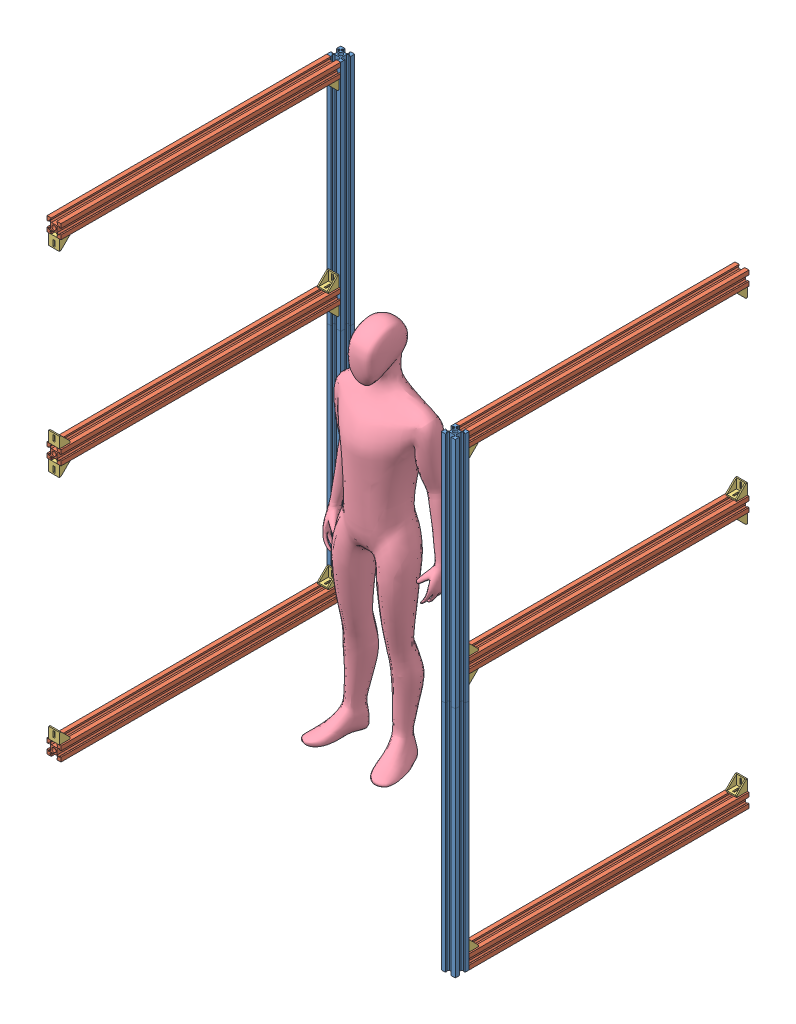
SolidWorks assembly FullFrameAssem, configuration Default. Lengths in mm.
Overall size (1732.26 2024.74 1278.93).
31 component instances, 4 part files, 10 mates.
Components (placement in the parent):
- RearSide-1: RearSide [Default] at (-737.6426 130.0792 3578.5624) x (0 0 -1) z (1 0 0) size (1260 2000 60)
  - AluminiumBar2M-1: AluminiumBar2M [Default] at (445.2282 96.0912 679.1807) size (60 2000 60)
    - AluminiumBar1M-1: AluminiumBar1M [Default] at (-159.6473 -25.0305 1080.6536) size (60 1000 60)
    - AluminiumBar1M-2: AluminiumBar1M [Default] at (-159.6473 974.9695 1080.6536) x (0 0 -1) z (1 0 0) size (60 1000 60)
  - AluminiumBar1.6M-1: AluminiumBar1.6M [Default] at (1515.5809 2041.0607 1759.8343) x (0 1 0) z (0 0 1) size (60 1200 60)
  - AluminiumBar1.6M-2: AluminiumBar1.6M [Default] at (1515.5809 1201.0607 1759.8343) x (0 1 0) z (0 0 1) size (60 1200 60)
  - AluminiumBar1.6M-3: AluminiumBar1.6M [Default] at (1515.5809 101.0607 1759.8343) x (0 1 0) z (0 0 1) size (60 1200 60)
  - Corner-2: Corner [Default] at (315.5809 2011.0607 1759.8343) x (-1 0 0) z (0 0 1) size (47 47 47)
  - Corner-3: Corner [Default] at (315.5809 1171.0607 1759.8343) x (-1 0 0) z (0 0 1) size (47 47 47)
  - Corner-4: Corner [Default] at (315.5809 1231.0607 1759.8343) x (-1 0 0) z (0 0 -1) size (47 47 47)
  - Corner-5: Corner [Default] at (315.5809 131.0607 1759.8343) x (-1 0 0) z (0 0 -1) size (47 47 47)
  - Corner-6: Corner [Default] at (1515.5809 1231.0607 1759.8343) size (47 47 47)
  - Corner-7: Corner [Default] at (1515.5809 2011.0607 1759.8343) x (1 0 0) z (0 0 -1) size (47 47 47)
  - Corner-8: Corner [Default] at (1515.5809 1171.0607 1759.8343) x (1 0 0) z (0 0 -1) size (47 47 47)
  - Corner-9: Corner [Default] at (1515.5809 131.0607 1759.8343) size (47 47 47)
- RearSide-2: RearSide [Default] at (1109.7642 105.3407 1826.3317) x (0 0 1) z (-1 0 0) size (1260 2000 60)
  - AluminiumBar2M-1: AluminiumBar2M [Default] at (445.2282 96.0912 679.1807) size (60 2000 60)
    - AluminiumBar1M-1: AluminiumBar1M [Default] at (-159.6473 -25.0305 1080.6536) size (60 1000 60)
    - AluminiumBar1M-2: AluminiumBar1M [Default] at (-159.6473 974.9695 1080.6536) x (0 0 -1) z (1 0 0) size (60 1000 60)
  - AluminiumBar1.6M-1: AluminiumBar1.6M [Default] at (1515.5809 2041.0607 1759.8343) x (0 1 0) z (0 0 1) size (60 1200 60)
  - AluminiumBar1.6M-2: AluminiumBar1.6M [Default] at (1515.5809 1201.0607 1759.8343) x (0 1 0) z (0 0 1) size (60 1200 60)
  - AluminiumBar1.6M-3: AluminiumBar1.6M [Default] at (1515.5809 101.0607 1759.8343) x (0 1 0) z (0 0 1) size (60 1200 60)
  - Corner-2: Corner [Default] at (315.5809 2011.0607 1759.8343) x (-1 0 0) z (0 0 1) size (47 47 47)
  - Corner-3: Corner [Default] at (315.5809 1171.0607 1759.8343) x (-1 0 0) z (0 0 1) size (47 47 47)
  - Corner-4: Corner [Default] at (315.5809 1231.0607 1759.8343) x (-1 0 0) z (0 0 -1) size (47 47 47)
  - Corner-5: Corner [Default] at (315.5809 131.0607 1759.8343) x (-1 0 0) z (0 0 -1) size (47 47 47)
  - Corner-6: Corner [Default] at (1515.5809 1231.0607 1759.8343) size (47 47 47)
  - Corner-7: Corner [Default] at (1515.5809 2011.0607 1759.8343) x (1 0 0) z (0 0 -1) size (47 47 47)
  - Corner-8: Corner [Default] at (1515.5809 1171.0607 1759.8343) x (1 0 0) z (0 0 -1) size (47 47 47)
  - Corner-9: Corner [Default] at (1515.5809 131.0607 1759.8343) size (47 47 47)
- Human-3: Human [Default] at (15.3034 1090.9118 2606.4903) x (1 0 0) z (0 1 0) size (494.2 289.03 1575.85)
Mates (geometry in assembly coordinates):
- Coincident1: coincident aligned: plane of FrontSide-1/AluminiumBar2.2M-3/AluminiumBar1.1M-1 through (-7.8083 201.1398 3304.9816) normal (0 -1 0); plane of RearSide-1/AluminiumBar1.6M-3 through (1034.1917 201.1398 3262.9816) normal (0 -1 0)
- Coincident2: coincident aligned: plane of RearSide-1/AluminiumBar1.6M-3 through (1010.1917 201.1398 3262.9816) normal (0 -1 0); plane of FrontSide-2/AluminiumBar2.2M-3/AluminiumBar1.1M-2 through (992.1917 201.1398 2044.9816) normal (0 -1 0)
- Coincident3: coincident aligned: plane of FrontSide-2/AluminiumBar2.2M-3/AluminiumBar1.1M-1 through (-7.8083 201.1398 2020.9816) normal (0 -1 0); plane of RearSide-2/AluminiumBar1.6M-3 through (-1025.8083 201.1398 2062.9816) normal (0 -1 0)
- Coincident4: coincident anti-aligned: plane of FrontSide-2/AluminiumBar2.2M-3/AluminiumBar1.1M-1 through (-1007.8083 231.1398 2032.9816) normal (-1 0 0); plane of RearSide-2/AluminiumBar2M-1/AluminiumBar1M-1 through (-1007.8083 1201.1398 2044.9816) normal (1 0 0)
- Coincident5: coincident aligned: plane of FrontSide-2/AluminiumBar2.2M-3/AluminiumBar1.1M-1 through (-7.8083 201.1398 2002.9816) normal (0 0 -1); plane of RearSide-2/AluminiumBar2M-1/AluminiumBar1M-1 through (-1025.8083 1201.1398 2002.9816) normal (0 0 -1)
- Coincident6: coincident aligned: plane of FrontSide-1/AluminiumBar2M-1/AluminiumBar1M-1 through (-1067.8083 1201.1398 3280.9816) normal (-1 0 0); plane of RearSide-2/AluminiumBar1.6M-3 through (-1067.8083 201.1398 2062.9816) normal (-1 0 0)
- Coincident7: coincident anti-aligned: plane of FrontSide-1/AluminiumBar2.2M-3/AluminiumBar1.1M-2 through (-1007.8083 201.1398 3262.9816) normal (0 0 -1); plane of RearSide-2/AluminiumBar1.6M-3 through (-1037.8083 231.1398 3262.9816) normal (0 0 1)
- Coincident8: coincident anti-aligned: plane of FrontSide-1/AluminiumBar2.2M-1/AluminiumBar1.1M-1 through (992.1917 2171.1398 3292.9816) normal (1 0 0); plane of RearSide-1/AluminiumBar2M-1/AluminiumBar1M-2 through (992.1917 2201.1398 3304.9816) normal (-1 0 0)
- Coincident9: coincident aligned: plane of FrontSide-1/AluminiumBar2.2M-1/AluminiumBar1.1M-1 through (-7.8083 2183.1398 3322.9816) normal (0 0 1); plane of RearSide-1/AluminiumBar2M-1/AluminiumBar1M-2 through (1010.1917 2201.1398 3322.9816) normal (0 0 1)
- Coincident10: coincident anti-aligned: plane of FrontSide-1/AluminiumBar2.2M-3/AluminiumBar1.1M-1 through (-7.8083 201.1398 3280.9816) normal (0 -1 0); plane of Human-3 through (15.3034 201.1398 2606.4903) normal (0 1 0)
